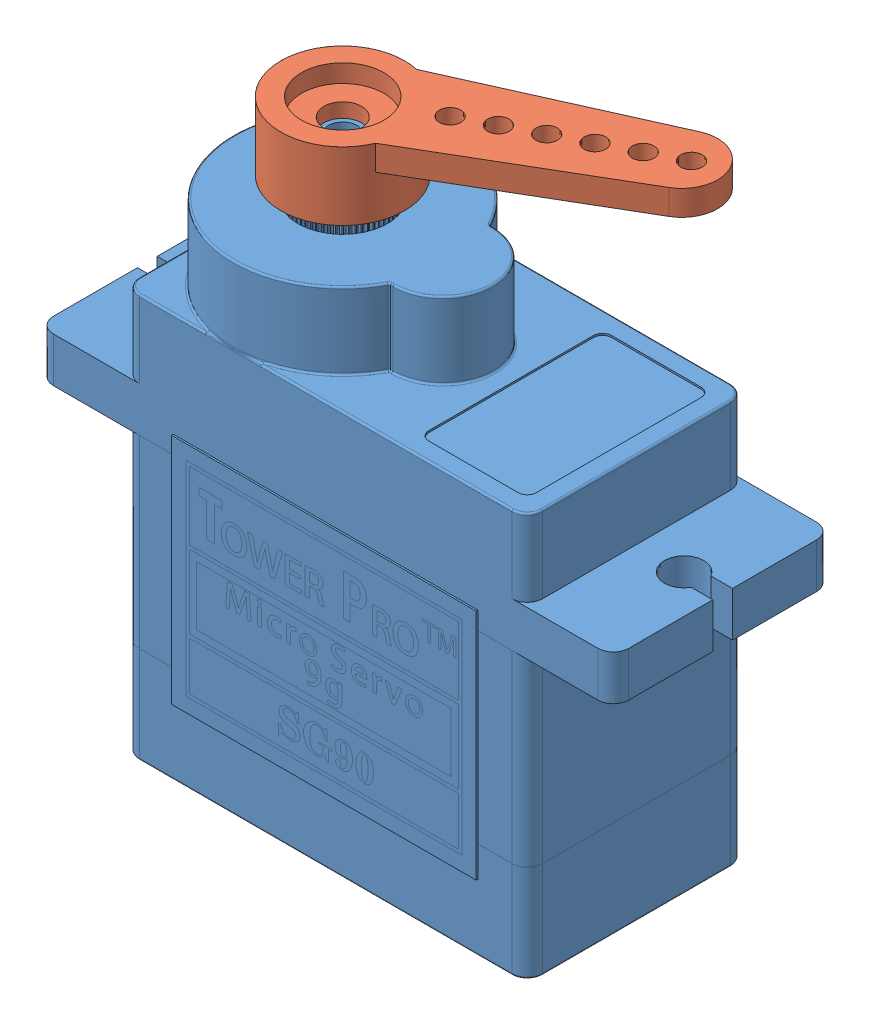
SolidWorks assembly Assem1, configuration Default. Lengths in mm.
Overall size (32.1 31.75 16.61).
2 component instances, 2 part files, 2 mates.
Components (placement in the parent):
- body-1: body [Peça] at (11.0042 8.2655 27.9824) size (32.1 29.95 12.4)
- horn-1: horn [Peça] at (5.8542 29.3655 27.9824) x (-0.88917 0 0.457577) z (-0.457577 0 -0.88917) size (19.5 3.8 6.9)
Mates (geometry in assembly coordinates):
- Concentric1: concentric: cylinder of assembly; cylinder of assembly; cylinder of body-1 through (5.8542 27.5655 27.9824) axis (0 1 0) radius 0.8; cylinder of horn-1 through (5.8542 29.3655 27.9824) axis (0 1 0) radius 1.05
- Coincident1: coincident: plane of assembly; plane of assembly; plane of body-1 through (5.8542 27.5655 27.9824) normal (0 1 0); plane of horn-1 through (5.8542 27.5655 27.9824) normal (0 -1 0)
